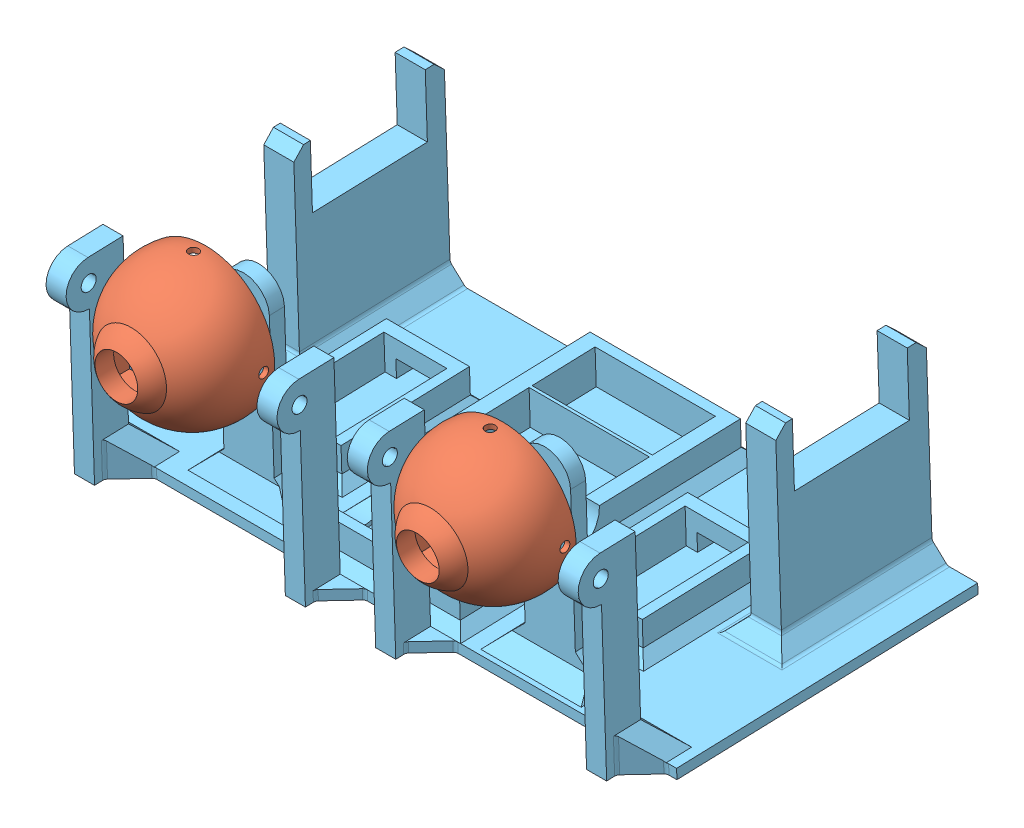
SolidWorks assembly EyeAssemblyFinal, configuration Default. Lengths in mm.
Overall size (120 49.81 82.5).
13 component instances, 5 part files, 10 mates.
Components (placement in the parent):
- UVHOLDERSLDPART-1: UVHOLDERSLDPART [Default] at (9.6546 9.8826 15.2328) size (20.5 15.75 3)
- eye ball-1: eye ball [Default] at (9.6546 9.8826 8.2328) x (0 0 -1) z (0 1 0) size (17.77 28 28)
- UVHOLDERSLDPART-2: UVHOLDERSLDPART [Default] at (69.6546 9.3742 15.216) x (1 0 0) z (0 -0.066023 0.997818) size (20.5 15.75 3)
- eye ball-2: eye ball [Default] at (69.6546 9.8364 8.2313) x (0 0.066023 -0.997818) z (0 -0.997818 -0.066023) size (17.77 28 28)
- UV_Final-1: UV_Final [Default] at (10.4248 15.8249 11.7172) x (-0.986642 -0.162816 -0.005381) z (0.162819 -0.986656 0) size (9.05 15.57 9.32)
  - UV cross spider[1].step-1: UV cross spider[1].step [Default] at (1.7499 4.175 5.7377) size (7.2 3 7.2)
  - UV Yoke[1].step-1: UV Yoke[1].step [Default] at (1.7499 11.8709 5.4867) x (1 0 0) z (0 -0.032589 -0.999469) size (9.01 10 9)
  - UV Yoke[1].step-2: UV Yoke[1].step [Default] at (1.7085 -3.5249 5.7377) x (0 0 -1) z (0.999986 -0.005381 0) size (9.01 10 9)
- UV_Final-2: UV_Final [Default] at (68.8845 3.6769 11.3157) x (0.986642 0.162816 0.005381) z (-0.162819 0.984503 0.065142) size (9.05 15.57 9.32)
  - UV cross spider[1].step-1: UV cross spider[1].step [Default] at (1.7499 4.175 5.7377) size (7.2 3 7.2)
  - UV Yoke[1].step-1: UV Yoke[1].step [Default] at (1.7499 11.8709 5.4867) x (1 0 0) z (0 -0.032589 -0.999469) size (9.01 10 9)
  - UV Yoke[1].step-2: UV Yoke[1].step [Default] at (1.7085 -3.5249 5.7377) x (0 0 -1) z (0.999986 -0.005381 0) size (9.01 10 9)
- BASE_v3_pasha-1: BASE_v3_pasha [Default] at (39.6546 -24.4519 -28.3208) x (-1 0 0) z (0 0.033029 -0.999454) size (120 40.7 71.5)
Mates (geometry in assembly coordinates):
- Coincident15: coincident anti-aligned: circle of UVHOLDERSLDPART-1; circle of UV_Final-1/UV Yoke[1].step-2
- Coincident17: coincident anti-aligned: circle of UVHOLDERSLDPART-2; circle of UV_Final-2/UV Yoke[1].step-2
- Coincident19: coincident anti-aligned: circle of UV_Final-1/UV Yoke[1].step-1; circle of BASE_v3_pasha-1
- Coincident20: coincident anti-aligned: circle of UV_Final-2/UV Yoke[1].step-1; circle of BASE_v3_pasha-1
- Parallel3: parallel aligned: line of UVHOLDERSLDPART-2 through (61.0052 3.8202 15.8507) axis (1 0 0); line of eye ball-2 through (64.6893 14.1975 16.5373) axis (1 0 0)
- Coincident22: coincident anti-aligned: plane of UVHOLDERSLDPART-2 through (69.6546 9.3082 16.2138) normal (0 -0.066023 0.997818); plane of eye ball-2 through (69.6546 9.3082 16.2138) normal (0 0.066023 -0.997818)
- Concentric4: concentric anti-aligned: circle of UVHOLDERSLDPART-2; circle of eye ball-2
- Parallel4: parallel anti-aligned: line of UVHOLDERSLDPART-1 through (1.0052 4.3826 15.2328) axis (1 0 0); line of eye ball-1 through (14.6199 4.9826 16.2328) axis (-1 0 0)
- Coincident24: coincident anti-aligned: plane of UVHOLDERSLDPART-1 through (9.6546 9.8826 16.2328) normal (0 0 1); plane of eye ball-1 through (9.6546 9.8826 16.2328) normal (0 0 -1)
- Concentric5: concentric anti-aligned: circle of UVHOLDERSLDPART-1; circle of eye ball-1
